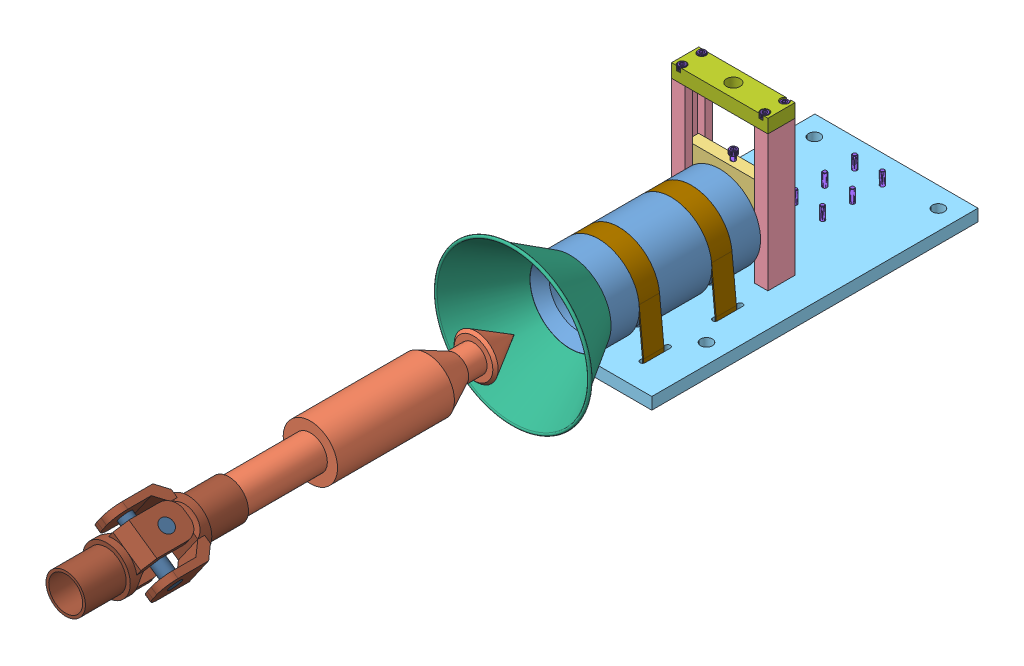
SolidWorks assembly Proto lock 1.0, configuration Default. Lengths in mm.
Overall size (182.99 194.28 776.21).
29 component instances, 11 part files, 53 mates.
Components (placement in the parent):
- 9056K221_Multipurpose_6061_Aluminum_Round_Tube (1)-1: 9056K221_Multipurpose_6061_Aluminum_Round_Tube (1) [9056K221] at (51.8711 64.1303 90.2778) size (76.2 76.2 139.7)
- 8996T14_24_oz._Tin_Funnel Extrude Cut-1: 8996T14_24_oz._Tin_Funnel Extrude Cut [8996T14] at (51.8711 64.1303 138.6828) x (1 0 0) z (0 -1 0) size (146.05 54.8 146.05) (hidden)
- Male Shaft Pointed-1: Male Shaft Pointed [Default] at (51.8711 64.1303 250.5394) x (0.999445 -0.033306 0) z (0 0 1) size (50.8 50.8 304.8)
- Lever lock-1: Lever lock [Default] at (51.8711 64.7922 2.1716) x (1 0 0) z (0 -1 0) size (76.2 11.11 76.2)
- Rail_tapped hole-3: Rail_tapped hole [Default] at (19.5663 26.0303 -4.9722) x (0 0 1) z (-1 0 0) size (25.4 127 12.7)
- Rail_tapped hole-2: Rail_tapped hole [Default] at (84.1759 26.0303 20.4278) x (0 0 -1) z (1 0 0) size (25.4 127 12.7)
- Base Plate-1: Base Plate [Default] at (-24.3289 14.9178 -144.6722) x (0 0 1) z (-1 0 0) size (304.8 11.11 152.4)
- 8996T14_24_oz._Tin_Funnel Extrude Cut-2: 8996T14_24_oz._Tin_Funnel Extrude Cut [8996T14] at (51.8711 64.1303 138.6828) x (-0.954405 -0.298516 0) z (-0.298516 0.954405 0) size (146.05 54.8 146.05)
- 1x.5 barstock-1: 1x.5 barstock [Default] at (6.8583 165.7303 -4.9722) x (0 0 1) z (0 1 0) size (25.4 90.02 12.7)
- 90128A197_Zinc-Plated Alloy Steel Socket Head Screw-1: 90128A197_Zinc-Plated Alloy Steel Socket Head Screw [90128A197] at (90.5259 26.6619 -1.4797) x (-0.441285 0 -0.897367) z (0 -1 0) size (6.87 6.87 23.83)
- 90128A197_Zinc-Plated Alloy Steel Socket Head Screw-2: 90128A197_Zinc-Plated Alloy Steel Socket Head Screw [90128A197] at (13.2163 26.7106 16.9353) x (-0.753245 0 -0.65774) z (0 -1 0) size (6.87 6.87 23.83)
- 90128A197_Zinc-Plated Alloy Steel Socket Head Screw-3: 90128A197_Zinc-Plated Alloy Steel Socket Head Screw [90128A197] at (13.2163 26.7164 -1.7972) x (-0.949473 0 -0.313849) z (0 -1 0) size (6.87 6.87 23.83)
- 90128A197_Zinc-Plated Alloy Steel Socket Head Screw-4: 90128A197_Zinc-Plated Alloy Steel Socket Head Screw [90128A197] at (90.5259 26.5793 16.9353) x (-0.929361 0 -0.369171) z (0 -1 0) size (6.87 6.87 23.83)
- 90128A197_Zinc-Plated Alloy Steel Socket Head Screw-5: 90128A197_Zinc-Plated Alloy Steel Socket Head Screw [90128A197] at (13.2163 155.1018 -1.4797) x (-0.9042 0 -0.427109) z (0 1 0) size (6.87 6.87 23.83)
- 90128A197_Zinc-Plated Alloy Steel Socket Head Screw-6: 90128A197_Zinc-Plated Alloy Steel Socket Head Screw [90128A197] at (90.5259 154.2711 16.9353) x (-0.835865 0 -0.548935) z (0 1 0) size (6.87 6.87 23.83)
- 90128A197_Zinc-Plated Alloy Steel Socket Head Screw-7: 90128A197_Zinc-Plated Alloy Steel Socket Head Screw [90128A197] at (13.2163 154.5322 16.9353) x (-0.876988 0 -0.480512) z (0 1 0) size (6.87 6.87 23.83)
- 90128A197_Zinc-Plated Alloy Steel Socket Head Screw-8: 90128A197_Zinc-Plated Alloy Steel Socket Head Screw [90128A197] at (90.5259 153.5032 -1.4797) x (-0.867719 0 -0.497056) z (0 1 0) size (6.87 6.87 23.83)
- 90128A197_Zinc-Plated Alloy Steel Socket Head Screw-9: 90128A197_Zinc-Plated Alloy Steel Socket Head Screw [90128A197] at (38.9375 26.5256 -62.7302) x (-0.837169 0 -0.546944) z (0 -1 0) size (6.87 6.87 23.83)
- 90128A197_Zinc-Plated Alloy Steel Socket Head Screw-10: 90128A197_Zinc-Plated Alloy Steel Socket Head Screw [90128A197] at (64.8047 26.5256 -62.7302) x (-0.837169 0 -0.546944) z (0 -1 0) size (6.87 6.87 23.83)
- 90128A197_Zinc-Plated Alloy Steel Socket Head Screw-11: 90128A197_Zinc-Plated Alloy Steel Socket Head Screw [90128A197] at (38.9375 26.5256 -118.6102) x (-0.837169 0 -0.546944) z (0 -1 0) size (6.87 6.87 23.83)
- 90128A197_Zinc-Plated Alloy Steel Socket Head Screw-12: 90128A197_Zinc-Plated Alloy Steel Socket Head Screw [90128A197] at (38.9375 26.5256 -90.6702) x (-0.837169 0 -0.546944) z (0 -1 0) size (6.87 6.87 23.83)
- 90128A197_Zinc-Plated Alloy Steel Socket Head Screw-13: 90128A197_Zinc-Plated Alloy Steel Socket Head Screw [90128A197] at (64.8047 26.5256 -118.6102) x (-0.837169 0 -0.546944) z (0 -1 0) size (6.87 6.87 23.83)
- 90128A197_Zinc-Plated Alloy Steel Socket Head Screw-14: 90128A197_Zinc-Plated Alloy Steel Socket Head Screw [90128A197] at (64.8047 26.5256 -90.6702) x (-0.837169 0 -0.546944) z (0 -1 0) size (6.87 6.87 23.83)
- Holding Bands-1: Holding Bands [Default] at (51.8711 64.1303 114.6067) size (84.14 85.91 19.05)
- Holding Bands-2: Holding Bands [Default] at (51.8711 64.1303 46.899) size (84.14 85.91 19.05)
- 90128A197_Zinc-Plated Alloy Steel Socket Head Screw-15: 90128A197_Zinc-Plated Alloy Steel Socket Head Screw [90128A197] at (51.8711 100.53 7.7278) x (-0.950207 0 -0.31162) z (0 1 0) size (6.87 6.87 23.83)
- CROSS-1: CROSS [Default] at (70.0051 90.1922 555.3394) x (-0.820847 0.571149 0) z (-0.571149 -0.820847 0) size (63.5 12.7 63.5)
- ARMS-1: ARMS [Default] at (51.8711 64.1303 479.1394) x (-0.820847 0.571149 0) z (0.571149 0.820847 0) size (63.5 95.25 44.45)
- ARMS-2: ARMS [Default] at (51.8711 64.1303 631.5394) x (0.571149 0.820847 0) z (-0.820847 0.571149 0) size (63.5 95.25 44.45)
Mates (geometry in assembly coordinates):
- Width1: width: plane of Lever lock-1 through (39.8787 68.8048 13.2841) normal (0.948324 -0.317305 0); plane of Lever lock-1 through (63.8635 68.8048 13.2841) normal (-0.948324 -0.317305 0); cylinder of 9056K221_Multipurpose_6061_Aluminum_Round_Tube (1)-1 through (51.8711 64.1303 160.1278) axis (0 0 -1) radius 28.575
- Parallel2: parallel: line of 9056K221_Multipurpose_6061_Aluminum_Round_Tube (1)-1 through (51.8711 26.0303 90.2778) axis (0 1 0); plane of Lever lock-1 through (89.9711 64.7922 13.2841) normal (1 0 0)
- Parallel4: parallel anti-aligned: plane of Lever lock-1 through (13.7711 64.7922 13.2841) normal (-1 0 0); plane of Rail-1 through (12.5011 153.0303 -4.9722) normal (1 0 0)
- Parallel5: parallel anti-aligned: plane of Lever lock-1 through (89.9711 64.7922 13.2841) normal (1 0 0); plane of Rail-2 through (91.2411 153.0303 20.4278) normal (-1 0 0)
- Width6: width aligned: plane of Rail_tapped hole-2 through (84.1759 153.0303 13.4428) normal (0 0 -1); plane of Rail_tapped hole-2 through (84.1759 153.0303 2.0128) normal (0 0 1); plane of Lever lock-1 through (51.8711 64.7922 2.1716) normal (0 0 -1); plane of Lever lock-1 through (51.8711 64.7922 13.2841) normal (0 0 1)
- Distance3: distance = 1.27 mm anti-aligned: plane of Lever lock-1 through (13.7711 64.7922 13.2841) normal (-1 0 0); plane of Rail-1 through (12.5011 153.0303 -4.9722) normal (1 0 0)
- Distance4: distance = 1.27 mm anti-aligned: plane of Lever lock-1 through (89.9711 64.7922 13.2841) normal (1 0 0); plane of Rail-2 through (91.2411 153.0303 20.4278) normal (-1 0 0)
- Width7: width anti-aligned: plane of Rail_tapped hole-2 through (96.8759 153.0303 20.4278) normal (1 0 0); plane of Rail_tapped hole-3 through (6.8663 153.0303 -4.9722) normal (-1 0 0); plane of Base Plate-1 through (-24.3289 26.0303 -144.6722) normal (-1 0 0); plane of Base Plate-1 through (128.0711 26.0303 -144.6722) normal (1 0 0)
- Coincident12: coincident anti-aligned: plane of 9056K221_Multipurpose_6061_Aluminum_Round_Tube (1)-1 through (51.8711 64.1303 20.4278) normal (0 0 -1); plane of Rail-1 through (19.5663 153.0303 20.4278) normal (0 0 1)
- Width8: width anti-aligned: plane of Lever lock-1 through (51.8711 64.7922 13.2841) normal (0 0 1); plane of Lever lock-1 through (51.8711 64.7922 2.1716) normal (0 0 -1); plane of Rail_tapped hole-3 through (19.5663 153.0303 13.4428) normal (0 0 -1); plane of Rail_tapped hole-3 through (19.5663 153.0303 2.0128) normal (0 0 1)
- Tangent1: tangent anti-aligned: cylinder of 9056K221_Multipurpose_6061_Aluminum_Round_Tube (1)-1 through (51.8711 64.1303 160.1278) axis (0 0 -1) radius 38.1; plane of Base Plate-1 through (-24.3289 26.0303 -144.6722) normal (0 1 0)
- Concentric8: concentric aligned: cylinder of 9056K221_Multipurpose_6061_Aluminum_Round_Tube (1)-1 through (51.8711 64.1303 160.1278) axis (0 0 -1) radius 38.1; circle of 8996T14_24_oz._Tin_Funnel Extrude Cut-2
- Coincident25: coincident anti-aligned: plane of 9056K221_Multipurpose_6061_Aluminum_Round_Tube (1)-1 through (51.8711 64.1303 160.1278) normal (0 0 1); plane of 8996T14_24_oz._Tin_Funnel Extrude Cut-2 through (37.2957 -16.9422 160.1278) normal (0 0 -1)
- Coincident26: coincident anti-aligned: plane of Rail_tapped hole-2 through (84.1759 26.0303 20.4278) normal (0 -1 0); plane of Base Plate-1 through (-24.3289 26.0303 -144.6722) normal (0 1 0)
- Coincident27: coincident anti-aligned: plane of Rail_tapped hole-3 through (19.5663 26.0303 -4.9722) normal (0 -1 0); plane of Base Plate-1 through (-24.3289 26.0303 -144.6722) normal (0 1 0)
- Coincident28: coincident anti-aligned: plane of Rail_tapped hole-2 through (84.1759 153.0303 20.4278) normal (0 1 0); plane of 1x.5 barstock-1 through (96.8759 153.0303 -4.9722) normal (0 -1 0)
- Coincident29: coincident aligned: plane of Rail_tapped hole-2 through (96.8759 153.0303 20.4278) normal (1 0 0); plane of 1x.5 barstock-1 through (96.8759 165.7303 -4.9722) normal (1 0 0)
- Coincident30: coincident aligned: plane of Rail_tapped hole-2 through (84.1759 153.0303 -4.9722) normal (0 0 -1); plane of 1x.5 barstock-1 through (96.8759 165.7303 -4.9722) normal (0 0 -1)
- Concentric9: concentric aligned: cylinder of Base Plate-1 through (90.5259 14.9178 -1.4797) axis (0 -1 0) radius 3.9688; cylinder of 90128A197_Zinc-Plated Alloy Steel Socket Head Screw-1 through (90.5259 15.0541 -1.4797) axis (0 -1 0) radius 3.429
- Width9: width anti-aligned: plane of Base Plate-1 through (-24.3289 26.0303 -144.6722) normal (0 0 -1); plane of 1x.5 barstock-1 through (-24.3289 26.0303 160.1278) normal (0 0 1); plane of Base Plate-1 through (96.8759 165.7303 20.4278) normal (0 0 1); plane of 1x.5 barstock-1 through (96.8759 165.7303 -4.9722) normal (0 0 -1)
- Concentric12: concentric aligned: cylinder of Base Plate-1 through (90.5259 14.9178 16.9353) axis (0 -1 0) radius 3.9688; cylinder of 90128A197_Zinc-Plated Alloy Steel Socket Head Screw-4 through (90.5259 14.9715 16.9353) axis (0 -1 0) radius 3.429
- Concentric13: concentric aligned: cylinder of Base Plate-1 through (13.2163 14.9178 16.9353) axis (0 -1 0) radius 3.9688; cylinder of 90128A197_Zinc-Plated Alloy Steel Socket Head Screw-2 through (13.2163 15.1028 16.9353) axis (0 -1 0) radius 3.429
- Concentric14: concentric aligned: cylinder of 1x.5 barstock-1 through (90.5259 165.7303 -1.4797) axis (0 1 0) radius 3.9688; cylinder of 90128A197_Zinc-Plated Alloy Steel Socket Head Screw-8 through (90.5259 165.111 -1.4797) axis (0 1 0) radius 3.429
- Concentric15: concentric aligned: cylinder of 1x.5 barstock-1 through (90.5259 165.7303 16.9353) axis (0 1 0) radius 3.9688; cylinder of 90128A197_Zinc-Plated Alloy Steel Socket Head Screw-6 through (90.5259 165.8789 16.9353) axis (0 1 0) radius 3.429
- Concentric16: concentric aligned: cylinder of 1x.5 barstock-1 through (13.2163 165.7303 16.9353) axis (0 1 0) radius 3.9688; cylinder of 90128A197_Zinc-Plated Alloy Steel Socket Head Screw-7 through (13.2163 166.14 16.9353) axis (0 1 0) radius 3.429
- Concentric17: concentric aligned: cylinder of 1x.5 barstock-1 through (13.2163 165.7303 -1.4797) axis (0 1 0) radius 3.9688; cylinder of 90128A197_Zinc-Plated Alloy Steel Socket Head Screw-5 through (13.2163 166.7096 -1.4797) axis (0 1 0) radius 3.429
- Concentric18: concentric aligned: cylinder of Base Plate-1 through (38.9375 14.9178 -118.6102) axis (0 -1 0) radius 3.9688; cylinder of 90128A197_Zinc-Plated Alloy Steel Socket Head Screw-11 through (38.9375 14.9178 -118.6102) axis (0 -1 0) radius 3.429
- Concentric19: concentric aligned: cylinder of Base Plate-1 through (38.9375 14.9178 -90.6702) axis (0 -1 0) radius 3.9688; cylinder of 90128A197_Zinc-Plated Alloy Steel Socket Head Screw-12 through (38.9375 14.9178 -90.6702) axis (0 -1 0) radius 3.429
- Concentric20: concentric aligned: cylinder of Base Plate-1 through (38.9375 14.9178 -62.7302) axis (0 -1 0) radius 3.9688; cylinder of 90128A197_Zinc-Plated Alloy Steel Socket Head Screw-9 through (38.9375 14.9178 -62.7302) axis (0 -1 0) radius 3.429
- Concentric21: concentric aligned: cylinder of Base Plate-1 through (64.8047 14.9178 -62.7302) axis (0 -1 0) radius 3.9688; cylinder of 90128A197_Zinc-Plated Alloy Steel Socket Head Screw-10 through (64.8047 14.9178 -62.7302) axis (0 -1 0) radius 3.429
- Concentric22: concentric aligned: cylinder of Base Plate-1 through (64.8047 14.9178 -90.6702) axis (0 -1 0) radius 3.9688; cylinder of 90128A197_Zinc-Plated Alloy Steel Socket Head Screw-14 through (64.8047 14.9178 -90.6702) axis (0 -1 0) radius 3.429
- Concentric23: concentric aligned: cylinder of Base Plate-1 through (64.8047 14.9178 -118.6102) axis (0 -1 0) radius 3.9688; cylinder of 90128A197_Zinc-Plated Alloy Steel Socket Head Screw-13 through (64.8047 14.9178 -118.6102) axis (0 -1 0) radius 3.429
- Coincident34: coincident anti-aligned: plane of Base Plate-1 through (64.8047 19.0834 -60.5776) normal (0 -1 0); plane of 90128A197_Zinc-Plated Alloy Steel Socket Head Screw-10 through (65.9439 19.0834 -64.4739) normal (0 1 0)
- Coincident35: coincident anti-aligned: plane of Base Plate-1 through (38.9375 19.0834 -60.5776) normal (0 -1 0); plane of 90128A197_Zinc-Plated Alloy Steel Socket Head Screw-9 through (40.0767 19.0834 -64.4739) normal (0 1 0)
- Coincident36: coincident anti-aligned: plane of Base Plate-1 through (64.8047 19.0834 -88.5176) normal (0 -1 0); plane of 90128A197_Zinc-Plated Alloy Steel Socket Head Screw-14 through (65.9439 19.0834 -92.4139) normal (0 1 0)
- Coincident37: coincident anti-aligned: plane of Base Plate-1 through (38.9375 19.0834 -88.5176) normal (0 -1 0); plane of 90128A197_Zinc-Plated Alloy Steel Socket Head Screw-12 through (40.0767 19.0834 -92.4139) normal (0 1 0)
- Coincident38: coincident anti-aligned: plane of Base Plate-1 through (64.8047 19.0834 -116.4576) normal (0 -1 0); plane of 90128A197_Zinc-Plated Alloy Steel Socket Head Screw-13 through (65.9439 19.0834 -120.3539) normal (0 1 0)
- Coincident39: coincident anti-aligned: plane of Base Plate-1 through (38.9375 19.0834 -116.4576) normal (0 -1 0); plane of 90128A197_Zinc-Plated Alloy Steel Socket Head Screw-11 through (40.0767 19.0834 -120.3539) normal (0 1 0)
- Coincident40: coincident aligned: circle of 9056K221_Multipurpose_6061_Aluminum_Round_Tube (1)-1; circle of Holding Bands-2
- Coincident41: coincident aligned: circle of 9056K221_Multipurpose_6061_Aluminum_Round_Tube (1)-1; circle of Holding Bands-1
- Parallel6: parallel aligned: plane of Base Plate-1 through (-24.3289 14.9178 -144.6722) normal (0 -1 0); plane of Holding Bands-2 through (9.8032 16.3229 65.949) normal (0 -1 0)
- Parallel7: parallel aligned: plane of Base Plate-1 through (-24.3289 14.9178 -144.6722) normal (0 -1 0); plane of Holding Bands-1 through (9.8032 16.3229 133.6567) normal (0 -1 0)
- Parallel8: parallel aligned: cylinder of 9056K221_Multipurpose_6061_Aluminum_Round_Tube (1)-1 through (51.8711 64.1303 160.1278) axis (0 0 -1) radius 28.575; cylinder of Male Shaft Pointed-1 through (51.8711 64.1303 402.9394) axis (0 0 -1) radius 25.4
- Concentric26: concentric aligned: cylinder of 9056K221_Multipurpose_6061_Aluminum_Round_Tube (1)-1 through (51.8711 64.1303 160.1278) axis (0 0 -1) radius 28.575; cylinder of Male Shaft Pointed-1 through (51.8711 64.1303 402.9394) axis (0 0 -1) radius 25.4
- Concentric27: concentric aligned: circle of Lever lock-1; circle of 90128A197_Zinc-Plated Alloy Steel Socket Head Screw-15
- Distance5: distance = 5.08 mm anti-aligned: plane of 90128A197_Zinc-Plated Alloy Steel Socket Head Screw-15 through (51.2221 107.9722 9.7069) normal (0 -1 0); plane of Lever lock-1 through (51.8711 102.8922 13.2841) normal (0 1 0)
- Concentric28: concentric anti-aligned: cylinder of Male Shaft Pointed-1 through (51.8711 64.1303 402.9394) axis (0 0 1) radius 15.875; cylinder of ARMS-1 through (51.8711 64.1303 517.2394) axis (0 0 -1) radius 15.875
- Coincident42: coincident anti-aligned: cylinder of CROSS-1 through (77.933 45.9964 555.3394) axis (-0.820847 0.571149 0) radius 6.35; circle of ARMS-1
- Coincident43: coincident aligned: plane of CROSS-1 through (77.933 45.9964 555.3394) normal (0.820847 -0.571149 0); plane of ARMS-1 through (87 59.0273 574.3894) normal (0.820847 -0.571149 0)
- Coincident44: coincident anti-aligned: plane of Male Shaft Pointed-1 through (51.8711 64.1303 517.2394) normal (0 0 1); plane of ARMS-1 through (51.8711 64.1303 517.2394) normal (0 0 -1)
- Coincident45: coincident aligned: plane of CROSS-1 through (33.7372 38.0685 555.3394) normal (-0.571149 -0.820847 0); plane of ARMS-2 through (20.7062 47.1355 536.2894) normal (-0.571149 -0.820847 0)
- Concentric29: concentric anti-aligned: cylinder of CROSS-1 through (33.7372 38.0685 555.3394) axis (0.571149 0.820847 0) radius 6.35; cylinder of ARMS-2 through (70.0051 90.1922 555.3394) axis (-0.571149 -0.820847 0) radius 6.35
- Concentric30: concentric anti-aligned: cylinder of ARMS-1 through (51.8711 64.1303 517.2394) axis (0 0 -1) radius 18.415; cylinder of ARMS-2 through (51.8711 64.1303 593.4394) axis (0 0 1) radius 18.415
